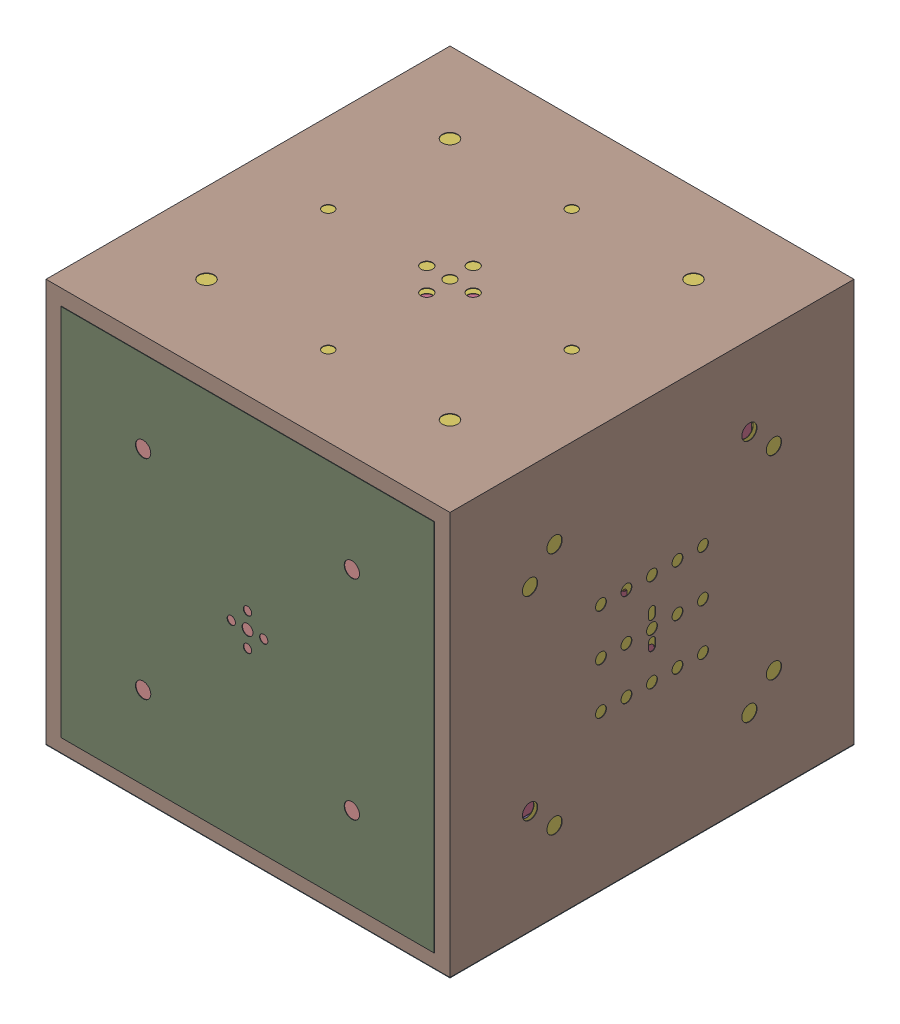
SolidWorks assembly MSR, configuration Default. Lengths in mm.
Overall size (3484 3477 3488).
10 component instances, 8 part files, 3 mates.
Components (placement in the parent):
- MSR_body-1: MSR_body [Default] at (0.4603 6.275 -6.7343) size (3484 3477 3484)
  - layer5-1: layer5 [Default] at (0 -1195 0) size (2390 2390 2390)
  - layer3-1: layer3 [Default] at (0 -1298.5 0) size (2600 2597 2600)
  - layer2-1: layer2 [Default] at (0 0 -1498.5) size (2997 2994 2997)
  - layer1-1: layer1 [Default] at (0 0 -1742) size (3484 3477 3484)
- MSR_door-1: MSR_door [Default] at (0 0 -88.4564) size (3220 3220 551)
  - layer1_door-1: layer1_door [Default] at (0 0 1823.7221) size (3220 3220 4)
  - layer2_door-2: layer2_door [Default] at (0 0 1580.2221) size (2840 2840 3)
  - layer3_door-1: layer3_door [Default] at (0 0 1381.7221) size (2580 2580 3)
  - layer5_door-1: layer5_door [Default] at (0 0 1276.7221) size (2160 2160 2)
Mates (geometry in assembly coordinates):
- Distance1: distance = 1610 mm: plane of assembly through (0 0 0) normal (0 1 0); plane of assembly; plane of MSR_door-1/layer1_door-1 through (-1610 1610 1739.2657) normal (0 1 0)
- Distance2: distance = 1610 mm: plane of assembly through (0 0 0) normal (1 0 0); plane of assembly; plane of MSR_door-1/layer1_door-1 through (-1610 1610 1739.2657) normal (-1 0 0)
- Coincident2: coincident anti-aligned: plane of MSR_body-1/layer5-1 through (-1194.5397 1201.275 1188.2657) normal (0 0 1); plane of MSR_door-1/layer5_door-1 through (0 0 1188.2657) normal (0 0 -1)
